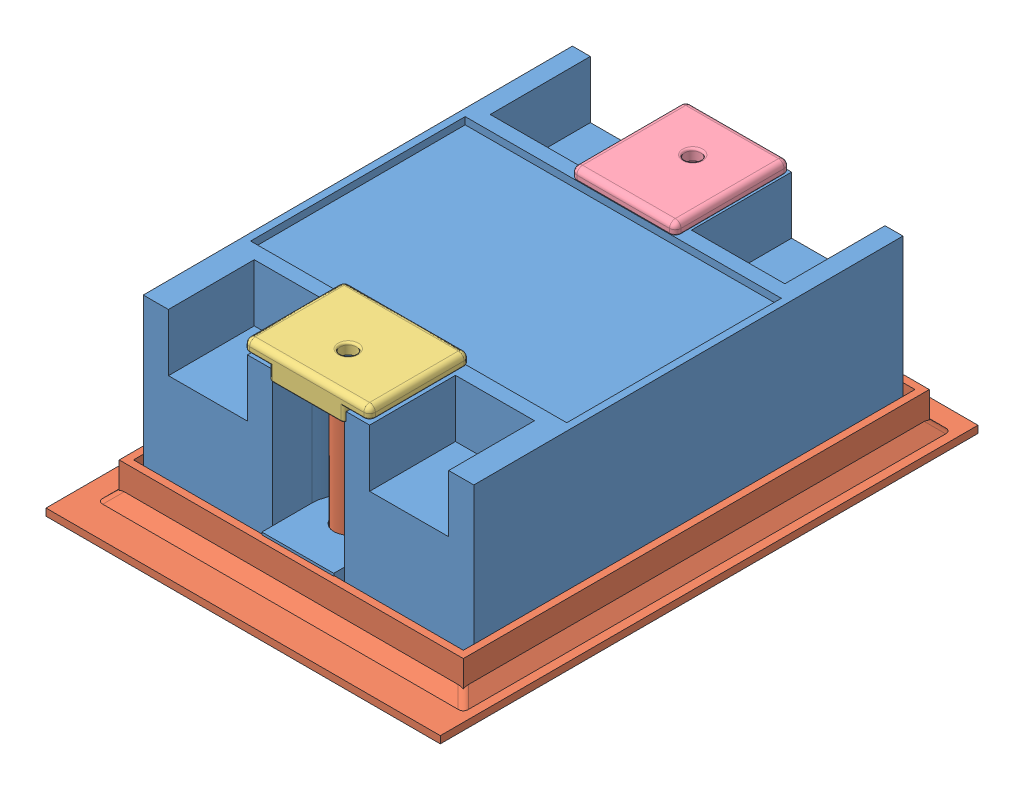
SolidWorks assembly Сборка2, configuration По умолчанию. Lengths in mm.
Overall size (55 27.44 75).
4 component instances, 4 part files, 9 mates.
Components (placement in the parent):
- дно-1: дно [По умолчанию] at (38.0957 -8.8718 95.9488) x (-0.999997 0 0.002403) z (-0.002403 0 -0.999997) size (46 24 63)
- крепление-1: крепление [По умолчанию] at (41.7746 -9.6253 49.2426) size (55 24 75)
- Крепление круг-1: Крепление круг [По умолчанию] at (45.4836 13.3131 88.5772) x (-0.999997 0 0.002403) z (-0.002403 0 -0.999997) size (17.5 3.52 14)
- Крепление овал-1: Крепление овал [По умолчанию] at (41.4122 12.7247 40.6446) x (0.999997 0 -0.002403) z (0.002403 0 0.999997) size (14.5 3.53 16.02)
Mates (geometry in assembly coordinates):
- Концентричный5: concentric: cylinder of дно-1 through (43.1985 -9.3753 88.8865) axis (0 1 0) radius 2; circle of крепление-1
- Расстояние3: distance = 0.225 mm: line of дно-1 through (40.9705 -4.2753 39.5617) axis (0.002403 0 0.999997); cylinder of крепление-1 through (43.1985 13.3747 40.8365) axis (0 -1 0) radius 2
- Граничное расстояние1: limit distance = 0.25 mm: plane of дно-1 through (66.064 -9.3753 32.8814) normal (0 -1 0); plane of крепление-1 through (41.7746 -9.6253 49.2426) normal (0 1 0)
- Концентричный6: concentric: circle of крепление-1; circle of Крепление овал-1
- Параллельность5: parallel: plane of дно-1 through (48.0676 14.6247 34.4247) normal (-0.002403 0 -0.999997); plane of Крепление овал-1 through (38.4334 14.7247 34.5479) normal (-0.002403 0 -0.999997)
- Граничное расстояние2: limit distance = 0.6884 mm: plane of Крепление круг-1 through (45.4836 15.3131 88.5772) normal (0 -1 0); plane of дно-1 through (43.2086 14.6247 88.9265) normal (0 1 0)
- Концентричный7: concentric: circle of крепление-1; circle of Крепление круг-1
- Параллельность6: parallel: plane of дно-1 through (38.2119 14.6247 94.4485) normal (0.002403 0 0.999997); plane of Крепление круг-1 through (48.4625 15.3131 94.6739) normal (0.002403 0 0.999997)
- Граничное расстояние4: limit distance = 0.1 mm: plane of Крепление овал-1 through (41.4122 14.7247 40.6446) normal (0 -1 0); plane of дно-1 through (43.2086 14.6247 88.9265) normal (0 1 0)
